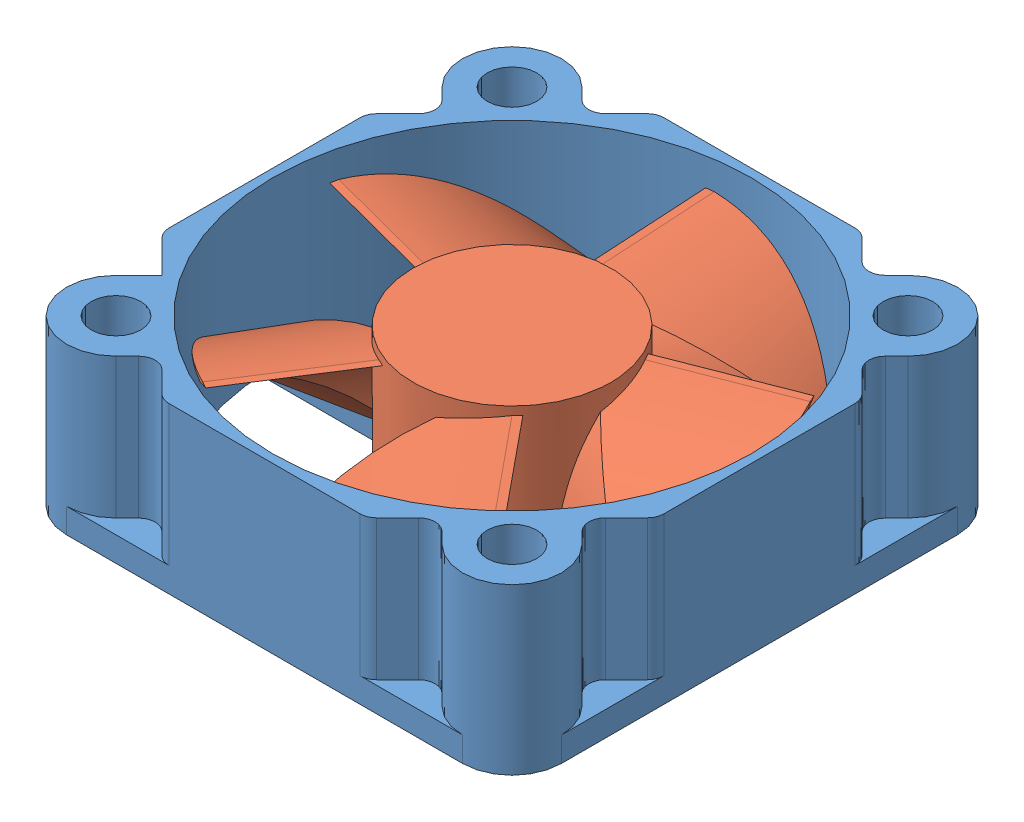
SolidWorks assembly Assem6, configuration Default. Lengths in mm.
Overall size (30 10 30).
2 component instances, 2 part files, 2 mates.
Components (placement in the parent):
- Fan Housing-1: Fan Housing [Varsayılan] at (11.9969 20.4661 22.7349) x (1 0 0) z (0 -1 0) size (30 30 10)
- Fan Blades-1: Fan Blades [Varsayılan] at (11.9969 15.9661 22.7349) x (1 0 0) z (0 1 0) size (27.42 27.42 8.73)
Mates (geometry in assembly coordinates):
- Coincident1: coincident: plane of Fan Housing-1 through (11.9969 11.9661 22.7349) normal (0 1 0); plane of Fan Blades-1 through (11.9969 11.9661 22.7349) normal (0 -1 0)
- Concentric1: concentric: cylinder of Fan Housing-1 through (11.9969 20.4661 22.7349) axis (0 -1 0) radius 14.5; cylinder of Fan Blades-1 through (11.9969 19.9661 22.7349) axis (0 -1 0) radius 6
